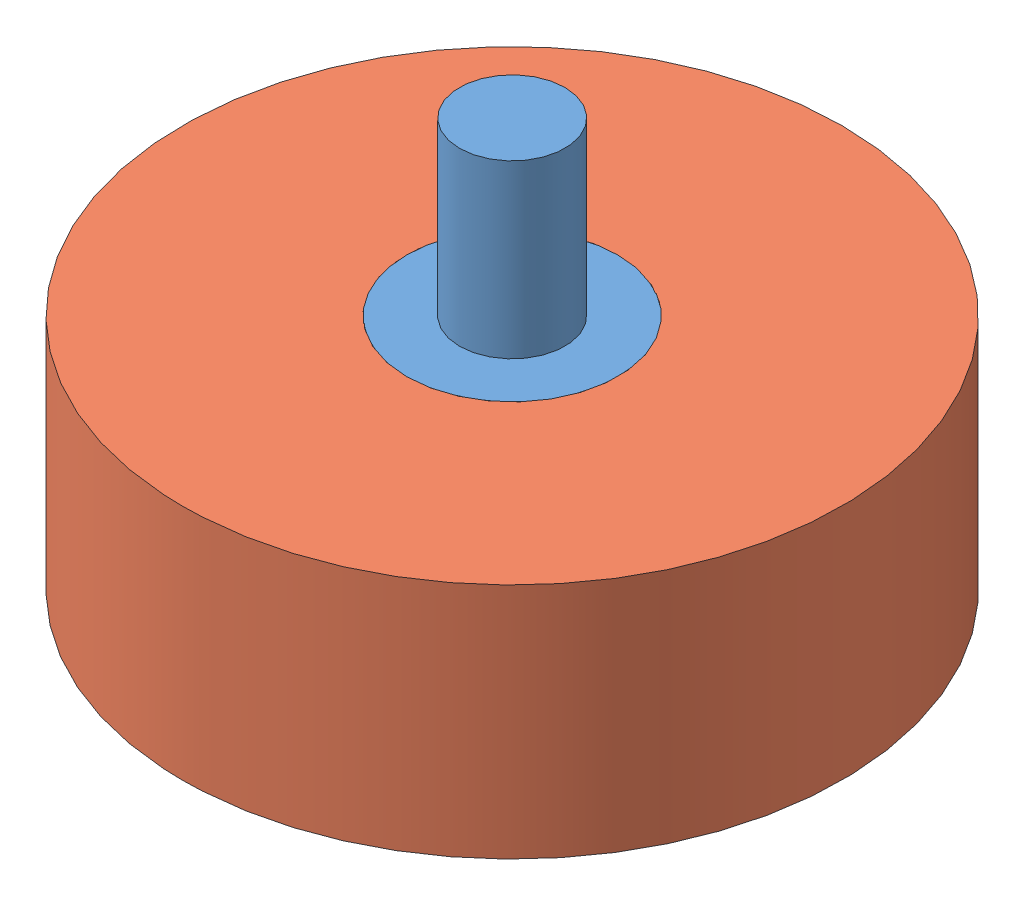
SolidWorks assembly 胶轮2, configuration 默认. Lengths in mm.
Overall size (50 44 50).
2 component instances, 2 part files, 1 mates.
Components (placement in the parent):
- 轮毂2-1: 轮毂2 [默认] at (-0.5766 -3.1773 48) size (16 44 16)
- 胶2-1: 胶2 [默认] at (-0.5766 -3.1773 48) size (50 18 50)
Mates (geometry in assembly coordinates):
- 重合1: coincident: circle of ?; circle of ?
